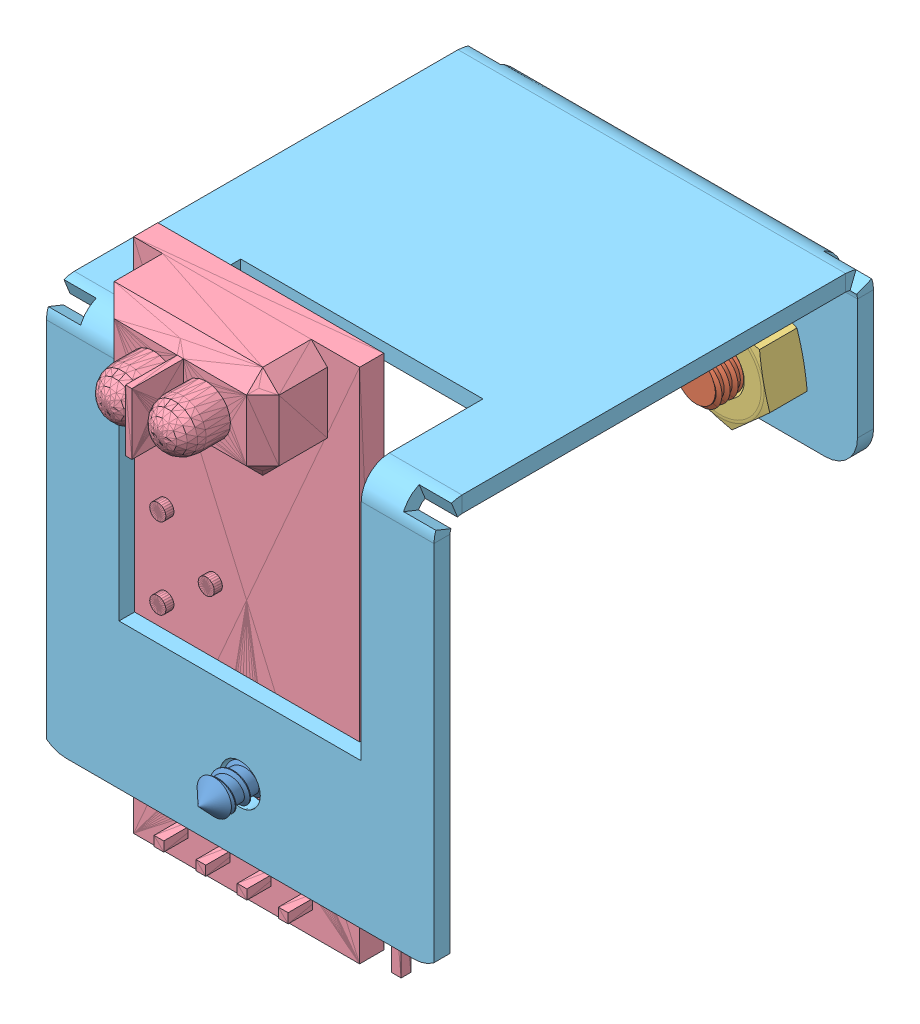
SolidWorks assembly LT, configuration Predeterminado. Lengths in mm.
Overall size (24 36.97 36.27).
7 component instances, 5 part files, 4 mates.
Components (placement in the parent):
- M2x6 SelfTap Screw-1: M2x6 SelfTap Screw [Predeterminado] at (151.0972 -212.5067 163.6331) x (-0.933732 -0.357972 0) z (0 0 -1) size (3.4 3.28 6)
- M3x6 Philips Screw-1: M3x6 Philips Screw [Predeterminado] at (157.0972 -199.1354 138.7994) x (-0.923728 -0.383049 0) z (0 0 -1) size (5.3 5.3 7.81)
- M3x6 Philips Screw-2: M3x6 Philips Screw [Predeterminado] at (145.0972 -199.1354 138.7994) x (-0.923728 -0.383049 0) z (0 0 -1) size (5.3 5.3 7.81)
- M3 Nut-1: M3 Nut [Predeterminado] at (145.0972 -199.1354 144.7994) size (6.27 6.27 2.71)
- M3 Nut-2: M3 Nut [Predeterminado] at (157.0972 -199.1354 144.7994) x (0.979048 0.203631 0) z (0 0 1) size (6.27 6.27 2.71)
- TCRT5000-2: TCRT5000 [Predeterminado] at (157.5351 -187.5137 164.5677) x (-1 0 0) z (0 0 1) size (14 36.97 13.8)
- TCTR5000_support-2: TCTR5000_support [Predeterminado] at (158.3422 -156.5965 140.7994) size (24 24.64 27.23)
Mates (geometry in assembly coordinates):
- Concéntrica255: concentric: circle of M3x6 Philips Screw-1; circle of TCTR5000_support-2
- Bloquear6: lock: unknown of TCRT5000-2; unknown of TCTR5000_support-2
- Coincidente1: coincident: plane of M3 Nut-2 through (157.3395 -200.1661 140.7994) normal (0 0 -1); plane of TCTR5000_support-2 through (141.0972 -201.1612 140.7994) normal (0 0 1)
- Concéntrica256: concentric: circle of M3 Nut-2; circle of TCTR5000_support-2
